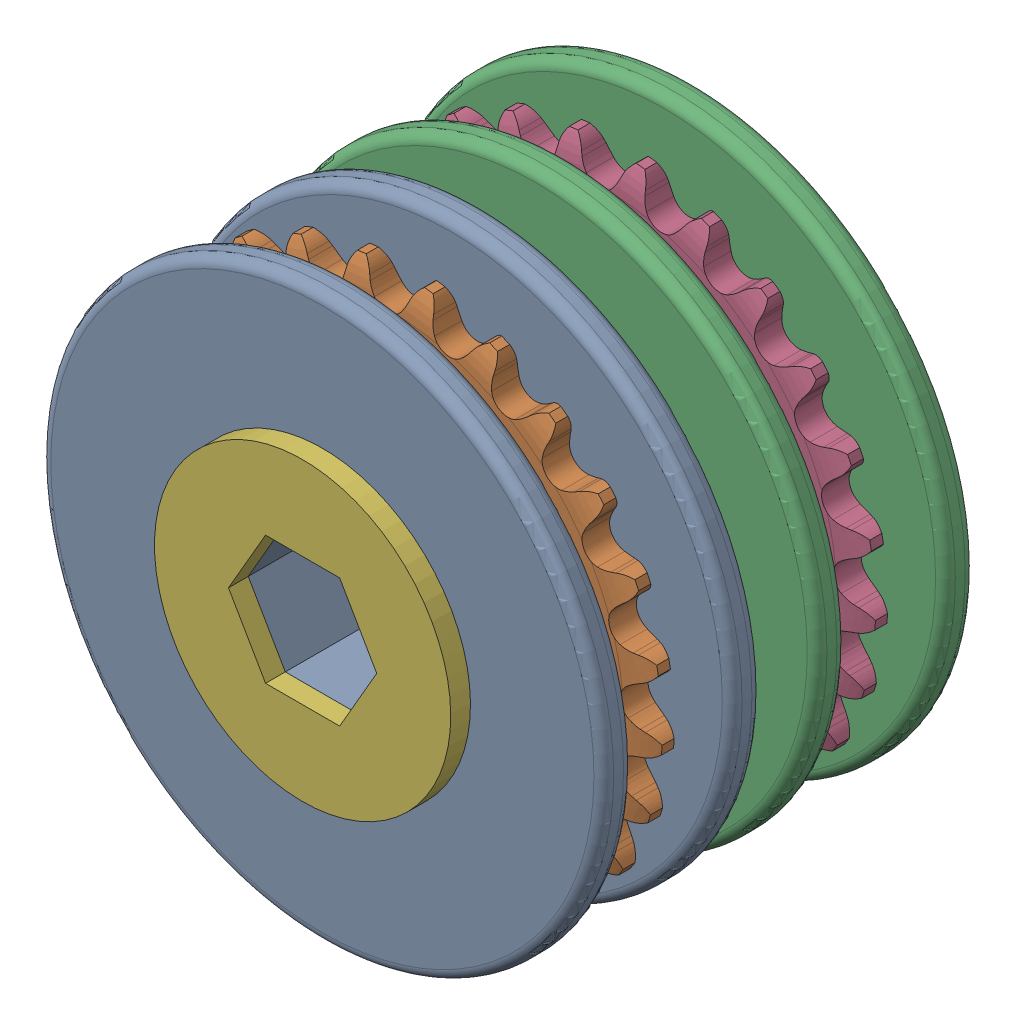
SolidWorks assembly motort, configuration Predeterminado. Lengths in mm.
Overall size (57.32 57.32 40.6).
5 component instances, 4 part files, 12 mates.
Components (placement in the parent):
- Sprocket_25-1: Sprocket_25 [Predeterminado] at (12.2355 4.0267 10.8167) size (57 57 16)
- Sprocket_25-2: Sprocket_25 [Predeterminado] at (12.2355 4.0267 -10.7833) x (0.999984 0.005704 0) z (0 0 1) size (57 57 16)
- Pieza1-2: Pieza1 [Predeterminado] at (12.2355 4.0267 -2.7833) x (0.999938 0.011163 0) z (0 0 1) size (30 30 5.6)
- Pieza2-2: Pieza2 [Predeterminado] at (12.2355 4.0267 18.8167) x (0.999938 0.011163 0) z (0 0 1) size (30 30 2)
- tapon-1: tapon [Predeterminado] at (12.2355 4.0267 -19.7833) x (0.999996 -0.002789 0) z (0 0 1) size (15.01 13.06 1)
Mates (geometry in assembly coordinates):
- Concéntrica1: concentric anti-aligned: circle of Sprocket_25-1; circle of Sprocket_25-2
- Distancia1: distance = 5.6 mm anti-aligned: plane of Sprocket_25-1 through (12.2355 4.0267 2.8167) normal (0 0 -1); plane of Sprocket_25-2 through (12.2355 4.0267 -2.7833) normal (0 0 1)
- Coincidente8: coincident aligned: plane of Sprocket_25-1 through (6.6063 0.7767 15.8167) normal (0.866025 0.5 0); plane of Pieza1-2 through (4.7299 4.0267 2.8167) normal (0.866025 0.5 0)
- Coincidente9: coincident aligned: plane of Sprocket_25-1 through (6.6063 7.2767 15.8167) normal (0.866025 -0.5 0); plane of Pieza1-2 through (8.4827 10.5267 2.8167) normal (0.866025 -0.5 0)
- Coincidente10: coincident aligned: plane of Sprocket_25-1 through (6.6063 7.2767 15.8167) normal (0.866025 -0.5 0); plane of Pieza1-2 through (8.4827 10.5267 2.8167) normal (0.866025 -0.5 0)
- Coincidente11: coincident anti-aligned: plane of Sprocket_25-1 through (12.2355 4.0267 2.8167) normal (0 0 -1); plane of Pieza1-2 through (12.2355 4.0267 2.8167) normal (0 0 1)
- Coincidente12: coincident aligned: plane of Sprocket_25-1 through (6.6063 0.7767 15.8167) normal (0.866025 0.5 0); plane of Pieza2-2 through (4.7299 4.0267 20.8167) normal (0.866025 0.5 0)
- Coincidente13: coincident aligned: plane of Sprocket_25-1 through (12.2355 -2.4733 15.8167) normal (0 1 0); plane of Pieza2-2 through (8.4827 -2.4733 20.8167) normal (0 1 0)
- Coincidente14: coincident anti-aligned: plane of Sprocket_25-1 through (12.2355 4.0267 18.8167) normal (0 0 1); plane of Pieza2-2 through (12.2355 4.0267 18.8167) normal (0 0 -1)
- Coincidente15: coincident: line of Sprocket_25-2 through (19.7409 4.0695 -18.7833) axis (-0.504931 0.86316 0); plane of tapon-1 through (19.7409 4.0695 -18.7833) normal (0.86316 0.504931 0)
- Coincidente16: coincident: line of Sprocket_25-2 through (15.9511 10.548 -18.7833) axis (-0.999984 -0.005704 0); plane of tapon-1 through (15.9511 10.548 -18.7833) normal (-0.005704 0.999984 0)
- Coincidente17: coincident anti-aligned: plane of Sprocket_25-2 through (12.2355 4.0267 -18.7833) normal (0 0 -1); plane of tapon-1 through (12.2355 4.0267 -18.7833) normal (0 0 1)
